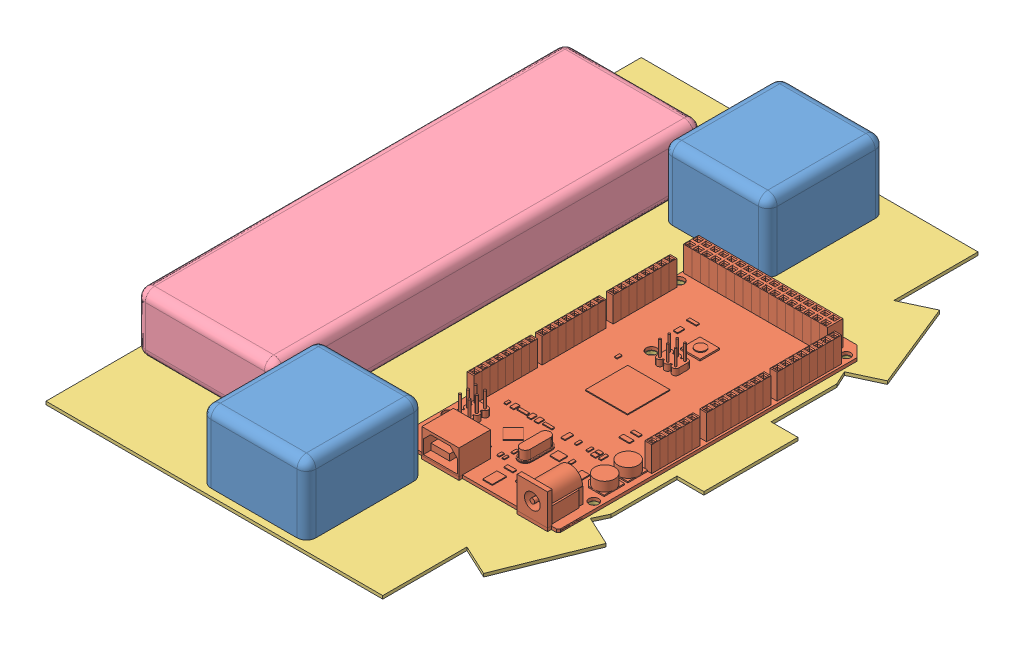
SolidWorks assembly Tapa_Conponents, configuration Predeterminado. Lengths in mm.
Overall size (130 23 190).
6 component instances, 5 part files, 10 mates.
Components (placement in the parent):
- esc-1: esc [Predeterminado] at (-62.1642 -31.5615 -180.2195) x (0 0 -1) z (1 0 0) size (37.3 22 33.5)
- esc-2: esc [Predeterminado] at (-63.1554 -31.5615 -33.9341) x (0 0 -1) z (1 0 0) size (37.3 22 33.5)
- ArduinoMega-3: ArduinoMega [Predeterminado] at (-34.2591 -31.5615 -106.9891) x (0 0 1) z (-1 0 0) size (100 11.65 51.63)
- base-2: base [Predeterminado] at (-62.2713 -31.5615 -108.0235) x (0 0 -1) z (0 -1 0) size (190 130 1)
- NFC_shield-2: NFC_shield [Default] at (-34.4646 -35.2615 -95.9146) x (0 0 1) z (-1 0 0) size (116.84 18.41 53.34) (hidden)
- PilaReal-1: PilaReal [Predeterminado] at (-103.7266 -31.5615 -108.6627) x (0 0 -1) z (0 1 0) size (137 44 19)
Mates (geometry in assembly coordinates):
- Coincidente9: coincident: plane of ArduinoMega-3 through (-34.2591 -31.5615 -106.9891) normal (0 -1 0); plane of base-2 through (-62.2713 -31.5615 -108.0235) normal (0 1 0)
- Coincidente11: coincident: plane of esc-2 through (-63.1554 -31.5615 -33.9341) normal (0 -1 0); plane of base-2 through (-62.2713 -31.5615 -108.0235) normal (0 1 0)
- Coincidente15: coincident: plane of esc-1 through (-62.1642 -31.5615 -180.2195) normal (0 -1 0); plane of base-2 through (-62.2713 -31.5615 -108.0235) normal (0 1 0)
- Paralelo1: parallel: plane of ArduinoMega-3 through (-34.2591 -30.5615 -106.9891) normal (0 1 0); plane of NFC_shield-2 through (-34.4646 -21.2915 -95.9146) normal (0 1 0)
- Paralelo2: parallel: plane of ArduinoMega-3 through (-59.186 -22.5615 -136.5546) normal (-1 0 0); plane of NFC_shield-2 through (-59.8646 -12.4015 -144.1746) normal (-1 0 0)
- Coincidente19: coincident: plane of ArduinoMega-3 through (-59.186 -22.5615 -144.1746) normal (0 0 -1); plane of NFC_shield-2 through (-57.3246 -12.4015 -144.1746) normal (0 0 -1)
- Coincidente22: coincident: plane of ArduinoMega-3 through (-34.2591 -22.5615 -62.5291) normal (0 1 0); plane of NFC_shield-2 through (-34.4646 -22.5615 -95.9146) normal (0 -1 0)
- Coincidente23: coincident: plane of base-2 through (-62.2713 -31.5615 -108.0235) normal (0 1 0); plane of PilaReal-1 through (-103.7266 -31.5615 -108.6627) normal (0 -1 0)
- Concéntrica1: concentric: cylinder of ArduinoMega-3 through (-11.2713 -40.5615 -152.4735) axis (0 1 0) radius 1.4101; cylinder of base-2 through (-11.2713 -41.5615 -152.4735) axis (0 1 0) radius 1.25
- Paralelo5: parallel: plane of ArduinoMega-3 through (-60.7591 -30.5615 -156.9891) normal (0 0 -1); plane of base-2 through (-127.2713 -32.5615 -203.0235) normal (0 0 -1)
